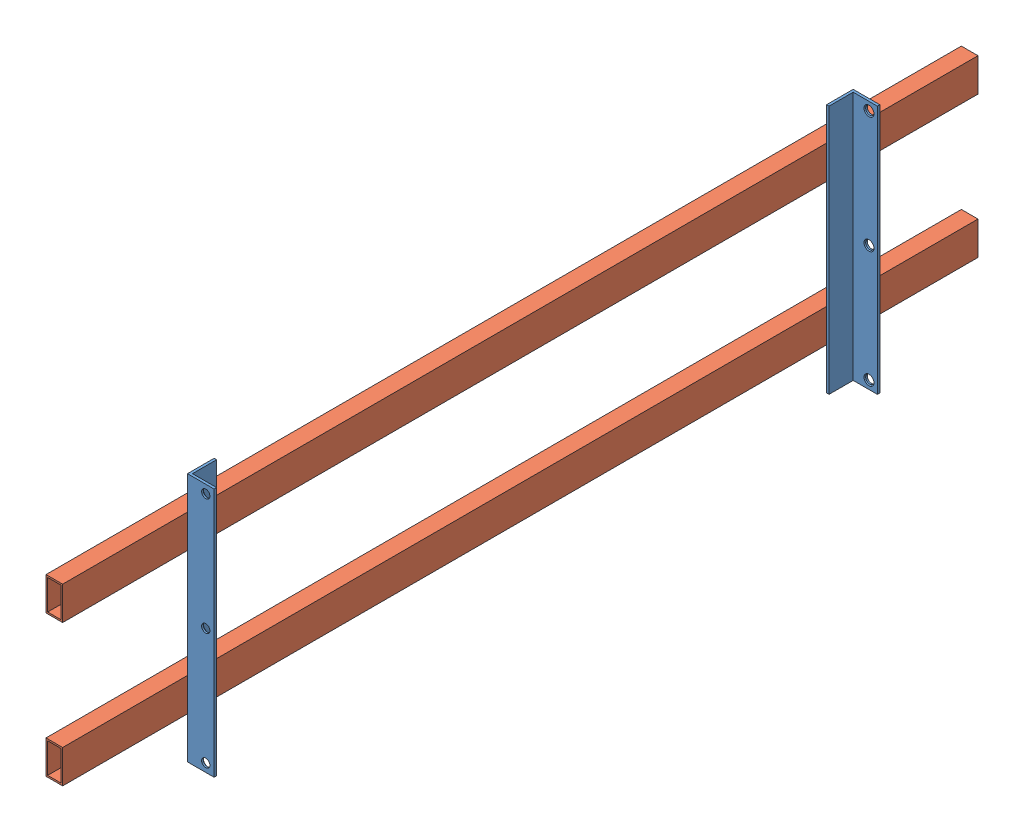
SolidWorks assembly ПерекладинаСбП, configuration По умолчанию. Lengths in mm.
Overall size (52 300 1100).
4 component instances, 2 part files, 10 mates.
Components (placement in the parent):
- Уголок32КОЗ-1: Уголок32КОЗ [По умолчанию] at origin size (32 300 32)
- Уголок32КОЗ-2: Уголок32КОЗ [По умолчанию] at (0 300 -800) x (1 0 0) z (0 0 -1) size (32 300 32)
- ПереклПроф-1: ПереклПроф [По умолчанию] at (-10 240 -950) x (1 0 0) z (0 -1 0) size (20 1100 40)
- ПереклПроф-2: ПереклПроф [По умолчанию] at (-10 70 -950) x (1 0 0) z (0 -1 0) size (20 1100 40)
Mates (geometry in assembly coordinates):
- Совпадение1: coincident: point of Уголок32КОЗ-1
- Совпадение2: coincident aligned: plane of Уголок32КОЗ-1 through (0 300 -32) normal (-1 0 0); plane of Уголок32КОЗ-2 through (0 0 -768) normal (-1 0 0)
- Расстояние1: distance = 800 mm anti-aligned: plane of Уголок32КОЗ-2 through (0 0 -800) normal (0 0 -1); plane of Уголок32КОЗ-1 through (0 300 0) normal (0 0 1)
- Совпадение4: coincident aligned: plane of Уголок32КОЗ-1 through (0 300 0) normal (0 1 0); plane of Уголок32КОЗ-2 through (0 300 -800) normal (0 1 0)
- Совпадение16: coincident anti-aligned: plane of Уголок32КОЗ-2 through (0 0 -768) normal (-1 0 0); plane of ПереклПроф-1 through (0 260 150) normal (1 0 0)
- Расстояние11: distance = 40 mm aligned: plane of ПереклПроф-1 through (-20 260 150) normal (0 1 0); plane of Уголок32КОЗ-2 through (0 300 -800) normal (0 1 0)
- Расстояние12: distance = 150 mm aligned: plane of ПереклПроф-1 through (-10 240 -950) normal (0 0 -1); plane of Уголок32КОЗ-2 through (0 0 -800) normal (0 0 -1)
- Совпадение19: coincident aligned: plane of ПереклПроф-1 through (-20 260 150) normal (-1 0 0); plane of ПереклПроф-2 through (-20 90 150) normal (-1 0 0)
- Совпадение20: coincident aligned: plane of ПереклПроф-1 through (-10 240 -950) normal (0 0 -1); plane of ПереклПроф-2 through (-10 70 -950) normal (0 0 -1)
- Расстояние13: distance = 130 mm anti-aligned: plane of ПереклПроф-2 through (-20 90 150) normal (0 1 0); plane of ПереклПроф-1 through (-20 220 150) normal (0 -1 0)
